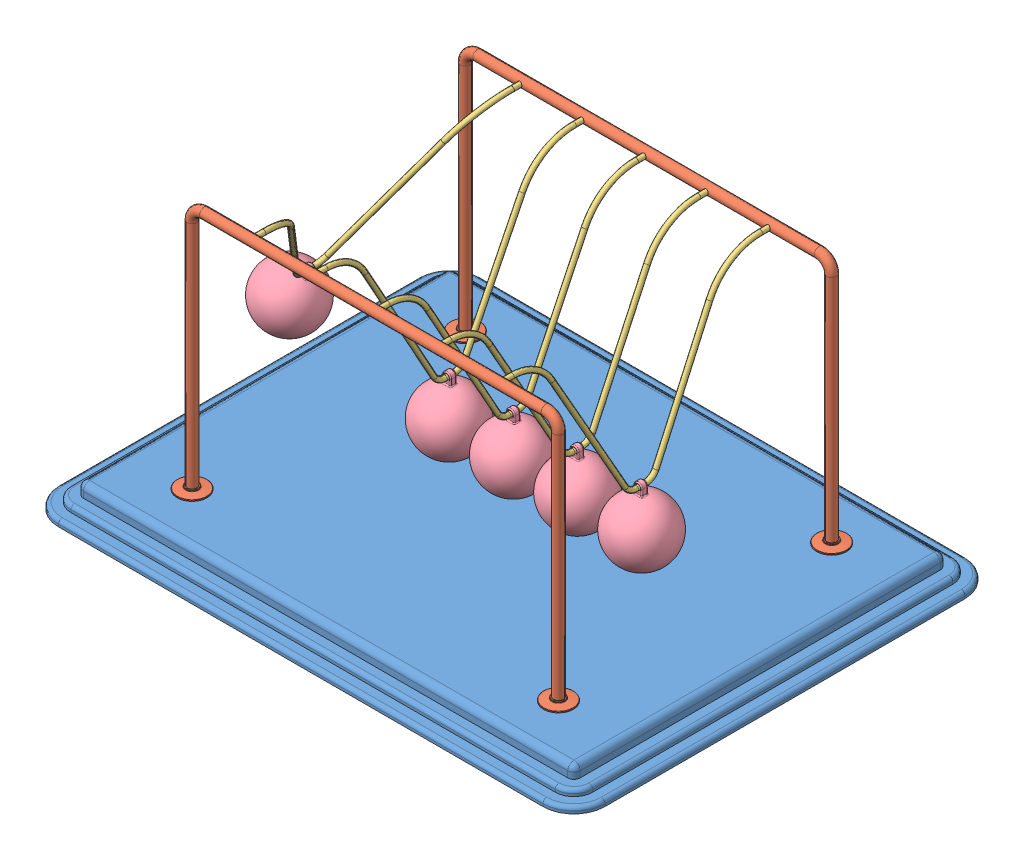
SolidWorks assembly Newtons Cradle NewtonsCradle 0255, configuration Default. Lengths in mm.
Overall size (440 222 340).
13 component instances, 4 part files, 34 mates.
Components (placement in the parent):
- Base 206,645056726094-1: Base 206,645056726094 [Default] at (-16.2968 -4.1587 11.425) size (440 20 340)
- frame NewtonsCradle 0255-1: frame NewtonsCradle 0255 [Default] at (-16.2968 144.4547 -98.575) size (319 202 24)
- frame NewtonsCradle 0255-2: frame NewtonsCradle 0255 [Default] at (-16.2968 144.4547 121.425) x (-1 0 0) z (0 0 -1) size (319 202 24)
- Hanging thing NewtonsCradle 0255-1: Hanging thing NewtonsCradle 0255 [Default] at (-157.6326 134.1825 11.425) x (0 0 1) z (-0.859985 0.510319 0) size (220 129 4)
- Hanging thing NewtonsCradle 0255-2: Hanging thing NewtonsCradle 0255 [Default] at (-66.576 122.8418 11.425) x (0 0 1) z (-0.999994 0.003446 0) size (220 129 4)
- Hanging thing NewtonsCradle 0255-3: Hanging thing NewtonsCradle 0255 [Default] at (-15.6923 122.8436 11.425) x (0 0 1) z (-0.999972 -0.007464 0) size (220 129 4)
- Hanging thing NewtonsCradle 0255-4: Hanging thing NewtonsCradle 0255 [Default] at (35.2213 122.8555 11.425) x (0 0 1) z (-0.999824 -0.018742 0) size (220 129 4)
- Hanging thing NewtonsCradle 0255-5: Hanging thing NewtonsCradle 0255 [Default] at (86.0287 122.8747 11.425) x (0 0 1) z (-0.999588 -0.028711 0) size (220 129 4)
- Sphere NewtonsCradle 0255-1: Sphere NewtonsCradle 0255 [Default] at (-195.3962 70.5436 11.425) x (0.859985 -0.510319 0) z (0 0 1) size (50 58.5 50)
- Sphere NewtonsCradle 0255-2: Sphere NewtonsCradle 0255 [Default] at (88.1533 48.9052 11.425) x (0.999588 0.028711 0) z (0 0 1) size (50 58.5 50)
- Sphere NewtonsCradle 0255-3: Sphere NewtonsCradle 0255 [Default] at (-15.14 48.8456 11.425) x (0.999972 0.007464 0) z (0 0 1) size (50 58.5 50)
- Sphere NewtonsCradle 0255-4: Sphere NewtonsCradle 0255 [Default] at (36.6081 48.8685 11.425) x (0.999824 0.018742 0) z (0 0 1) size (50 58.5 50)
- Sphere NewtonsCradle 0255-5: Sphere NewtonsCradle 0255 [Default] at (-66.831 48.8422 11.425) x (0.999994 -0.003446 0) z (0 0 1) size (50 58.5 50)
Mates (geometry in assembly coordinates):
- Coincident1: coincident anti-aligned: plane of Base-1 through (-211.2968 5.8413 156.425) normal (0 1 0); plane of frame-2 through (-175.7968 5.8413 121.425) normal (0 -1 0)
- Coincident2: coincident anti-aligned: plane of Base-1 through (-211.2968 5.8413 156.425) normal (0 1 0); plane of frame-1 through (143.2032 5.8413 -98.575) normal (0 -1 0)
- Concentric1: concentric anti-aligned: cylinder of frame-1 through (-116.2968 203.8413 -94.575) axis (0 0 -1) radius 2; cylinder of frame-2 through (-116.2968 203.8413 117.425) axis (0 0 1) radius 2
- Concentric2: concentric anti-aligned: cylinder of frame-1 through (83.7032 203.8413 -94.575) axis (0 0 -1) radius 2; cylinder of frame-2 through (83.7032 203.8413 117.425) axis (0 0 1) radius 2
- Distance1: distance = 60 mm: plane of frame-1 through (-16.2968 144.4547 -98.575) normal (0 0 1); line of Base-1 through (-211.2968 -12.1587 -158.575) axis (1 0 0)
- Distance2: distance = 60 mm: line of Base-1 through (178.7032 -12.1587 181.425) axis (-1 0 0); plane of frame-2 through (-16.2968 144.4547 121.425) normal (0 0 -1)
- Distance3: distance = 220 mm: plane of frame-2 through (-16.2968 144.4547 121.425) normal (-1 0 0); line of Base-1 through (-236.2968 -12.1587 156.425) axis (0 0 -1)
- Concentric3: concentric anti-aligned: cylinder of frame-1 through (-116.2968 203.8413 -94.575) axis (0 0 -1) radius 2; cylinder of Hanging thing-1 through (-116.2968 203.8413 111.425) axis (0 0 1) radius 2
- Concentric4: concentric anti-aligned: cylinder of frame-1 through (-116.2968 203.8413 -94.575) axis (0 0 -1) radius 2; cylinder of Hanging thing-1 through (-116.2968 203.8413 -98.575) axis (0 0 1) radius 2
- Concentric5: concentric aligned: cylinder of frame-2 through (-66.2968 203.8413 117.425) axis (0 0 1) radius 2; cylinder of Hanging thing-2 through (-66.2968 203.8413 111.425) axis (0 0 1) radius 2
- Concentric6: concentric aligned: cylinder of frame-2 through (-16.2968 203.8413 117.425) axis (0 0 1) radius 2; cylinder of Hanging thing-3 through (-16.2968 203.8413 111.425) axis (0 0 1) radius 2
- Concentric7: concentric aligned: cylinder of frame-2 through (33.7032 203.8413 117.425) axis (0 0 1) radius 2; cylinder of Hanging thing-4 through (33.7032 203.8413 111.425) axis (0 0 1) radius 2
- Concentric8: concentric aligned: cylinder of frame-2 through (83.7032 203.8413 117.425) axis (0 0 1) radius 2; cylinder of Hanging thing-5 through (83.7032 203.8413 111.425) axis (0 0 1) radius 2
- Coincident5: coincident anti-aligned: plane of frame-2 through (83.7032 203.8413 121.425) normal (0 0 -1); plane of Hanging thing-5 through (83.7032 203.8413 121.425) normal (0 0 1)
- Coincident6: coincident anti-aligned: plane of frame-2 through (33.7032 203.8413 121.425) normal (0 0 -1); plane of Hanging thing-4 through (33.7032 203.8413 121.425) normal (0 0 1)
- Coincident7: coincident anti-aligned: plane of frame-2 through (-16.2968 203.8413 121.425) normal (0 0 -1); plane of Hanging thing-3 through (-16.2968 203.8413 121.425) normal (0 0 1)
- Coincident8: coincident anti-aligned: plane of frame-2 through (-66.2968 203.8413 121.425) normal (0 0 -1); plane of Hanging thing-2 through (-66.2968 203.8413 121.425) normal (0 0 1)
- Coincident9: coincident anti-aligned: plane of frame-2 through (-116.2968 203.8413 121.425) normal (0 0 -1); plane of Hanging thing-1 through (-116.2968 203.8413 121.425) normal (0 0 1)
- Concentric9: concentric anti-aligned: cylinder of Hanging thing-1 through (-117.0163 78.8434 7.925) axis (0 0 1) radius 2; cylinder of Sphere-1 through (-117.0163 78.8434 13.925) axis (0 0 -1) radius 2
- Concentric13: concentric anti-aligned: cylinder of Hanging thing-2 through (-66.7276 78.842 7.925) axis (0 0 1) radius 2; cylinder of Sphere-5 through (-66.7276 78.842 13.925) axis (0 0 -1) radius 2
- Concentric15: concentric anti-aligned: cylinder of Hanging thing-3 through (-15.3639 78.8448 7.925) axis (0 0 1) radius 2; cylinder of Sphere-3 through (-15.3639 78.8448 13.925) axis (0 0 -1) radius 2
- Concentric16: concentric anti-aligned: cylinder of Hanging thing-5 through (87.292 78.8928 7.925) axis (0 0 1) radius 2; cylinder of Sphere-2 through (87.292 78.8928 13.925) axis (0 0 -1) radius 2
- Concentric17: concentric anti-aligned: cylinder of Hanging thing-4 through (36.0459 78.8632 7.925) axis (0 0 1) radius 2; cylinder of Sphere-4 through (36.0459 78.8632 13.925) axis (0 0 -1) radius 2
- Parallel1: parallel anti-aligned: plane of Hanging thing-1; plane of Sphere-1
- Coincident22: coincident anti-aligned: plane of Hanging thing-1; plane of Sphere-1
- Coincident12: coincident aligned: plane of Hanging thing-2 through (-66.576 122.8418 11.425) normal (0 0 1); plane of Sphere-5 through (-66.831 48.8422 11.425) normal (0 0 1)
- Coincident10: coincident aligned: plane of Hanging thing-1 through (-116.763 122.8426 11.425) normal (0 0 1); plane of Sphere-1 through (-118.5806 48.8842 11.425) normal (0 0 1)
- Coincident13: coincident anti-aligned: plane of Hanging thing-2 through (-66.576 122.8418 11.425) normal (-0.999994 0.003446 0); plane of Sphere-5 through (-66.831 48.8422 11.425) normal (0.999994 -0.003446 0)
- Coincident14: coincident anti-aligned: plane of Hanging thing-3 through (-15.6923 122.8436 11.425) normal (-0.999972 -0.007464 0); plane of Sphere-3 through (-15.14 48.8456 11.425) normal (0.999972 0.007464 0)
- Coincident15: coincident aligned: plane of Hanging thing-3 through (-15.6923 122.8436 11.425) normal (0 0 1); plane of Sphere-3 through (-15.14 48.8456 11.425) normal (0 0 1)
- Coincident18: coincident aligned: plane of Hanging thing-4 through (35.2213 122.8555 11.425) normal (0 0 1); plane of Sphere-4 through (36.6081 48.8685 11.425) normal (0 0 1)
- Coincident19: coincident anti-aligned: plane of Hanging thing-4 through (35.2213 122.8555 11.425) normal (-0.999824 -0.018742 0); plane of Sphere-4 through (36.6081 48.8685 11.425) normal (0.999824 0.018742 0)
- Coincident20: coincident anti-aligned: plane of Hanging thing-5 through (86.0287 122.8747 11.425) normal (-0.999588 -0.028711 0); plane of Sphere-2 through (88.1533 48.9052 11.425) normal (0.999588 0.028711 0)
- Coincident21: coincident aligned: plane of Hanging thing-5 through (86.0287 122.8747 11.425) normal (0 0 1); plane of Sphere-2 through (88.1533 48.9052 11.425) normal (0 0 1)
